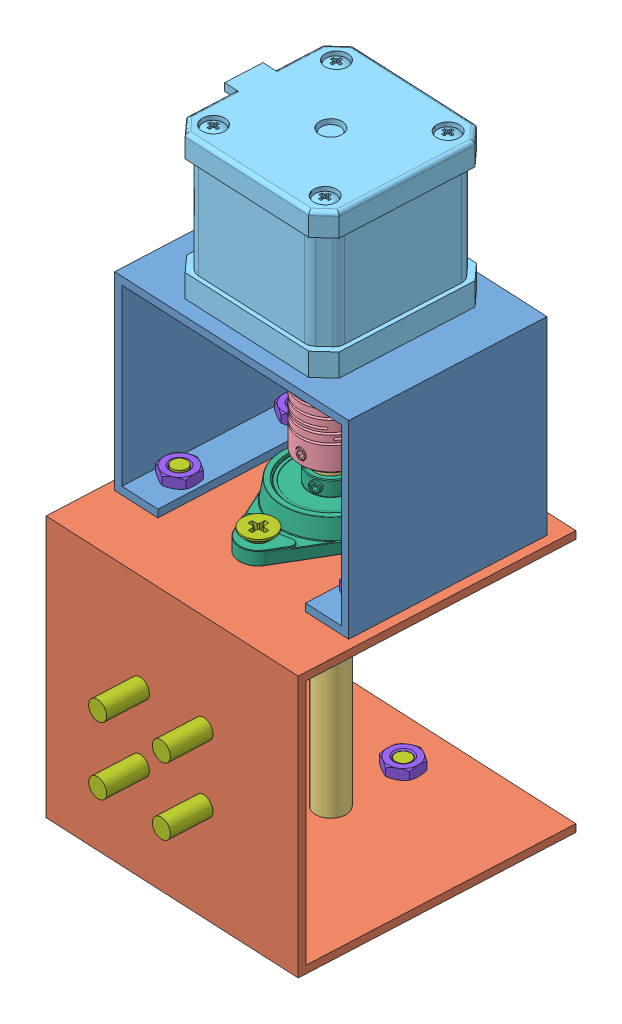
SolidWorks assembly Junta4-Assembly, configuration Valor predeterminado. Lengths in mm.
Overall size (73.29 177 83).
31 component instances, 8 part files, 60 mates.
Components (placement in the parent):
- Junta 4 parte 1-1: Junta 4 parte 1 [Valor predeterminado] at (-23.3214 57.6883 49.324) x (0.998842 0 0.04812) z (-0.04812 0 0.998842) size (65 50 50)
- Junta 4 parte 2-2: Junta 4 parte 2 [Valor predeterminado] at (-52.5649 -26.8117 32.8978) x (0 1 0) z (0.998842 0 0.04812) size (69 70 70)
- Eixo 4-1: Eixo 4 [Valor predeterminado] at (-23.3214 -81.3117 49.324) size (8 110 8)
- Acoplamento Flexível MSTS-16-5-8-1: Acoplamento Flexível MSTS-16-5-8 [Valor predeterminado] at (-23.3214 45.1883 49.324) x (0 -1 0) z (0 0 1) size (23 16 16)
- NEMA17-1: NEMA17 [Défaut] at (-23.3214 55.6883 49.324) x (0.998842 0 0.04812) z (0 1 0) size (45.3 42.3 62)
- Rolamento KFL08 Ø8-1: Rolamento KFL08 Ø8 [Valor predeterminado] at (-23.3214 7.6883 49.324) x (0.04812 0 -0.998842) z (0.998842 0 0.04812) size (47.88 11.35 28.12)
- Rolamento KFL08 Ø8-2: Rolamento KFL08 Ø8 [Valor predeterminado] at (-23.3214 -61.3117 49.324) x (0.04812 0 -0.998842) z (-0.998842 0 -0.04812) size (47.88 11.35 28.12)
- countersunk flat head cross recess screw_iso-1: countersunk flat head cross recess screw_iso [ISO 7046-1 - M5 x 16 - Z - 16N] at (-16.1656 -17.9729 84.4706) x (-0.04812 0 0.998842) z (-0.015193 -0.999884 -0.000732) size (16 9.3 9.3)
- countersunk flat head cross recess screw_iso-2: countersunk flat head cross recess screw_iso [ISO 7046-1 - M5 x 16 - Z - 16N] at (-16.1656 -35.6506 84.4706) x (-0.04812 0 0.998842) z (-0.015193 -0.999884 -0.000732) size (16 9.3 9.3)
- countersunk flat head cross recess screw_iso-3: countersunk flat head cross recess screw_iso [ISO 7046-1 - M5 x 16 - Z - 16N] at (-33.8227 -17.9729 83.6199) x (-0.04812 0 0.998842) z (-0.015193 -0.999884 -0.000732) size (16 9.3 9.3)
- countersunk flat head cross recess screw_iso-4: countersunk flat head cross recess screw_iso [ISO 7046-1 - M5 x 16 - Z - 16N] at (-33.8227 -35.6506 83.6199) x (-0.04812 0 0.998842) z (-0.015193 -0.999884 -0.000732) size (16 9.3 9.3)
- countersunk flat head cross recess screw_iso-9: countersunk flat head cross recess screw_iso [ISO 7046-1 - M4 x 10 - Z - 10N] at (-22.4432 13.2383 31.0952) x (0 -1 0) z (0.999954 0 -0.009545) size (10 8.4 8.4)
- countersunk flat head cross recess screw_iso-12: countersunk flat head cross recess screw_iso [ISO 7046-1 - M4 x 10 - Z - 10N] at (-24.1996 13.2383 67.5529) x (0 -1 0) z (0.999954 0 -0.009545) size (10 8.4 8.4)
- countersunk flat head cross recess screw_iso-13: countersunk flat head cross recess screw_iso [ISO 7046-1 - M4 x 10 - Z - 10N] at (-22.4432 -66.8617 31.0952) x (0 1 0) z (-0.83191 0 -0.55491) size (10 8.4 8.4)
- countersunk flat head cross recess screw_iso-14: countersunk flat head cross recess screw_iso [ISO 7046-1 - M4 x 10 - Z - 10N] at (-24.1996 -66.8617 67.5529) x (0 1 0) z (-0.83191 0 -0.55491) size (10 8.4 8.4)
- countersunk flat head cross recess screw_iso-15: countersunk flat head cross recess screw_iso [ISO 7046-1 - M3 x 6 - Z - 6N] at (-8.5852 53.7069 65.5519) x (0 1 0) z (0.179864 0 -0.983691) size (6 5.5 5.5)
- countersunk flat head cross recess screw_iso-16: countersunk flat head cross recess screw_iso [ISO 7046-1 - M3 x 6 - Z - 6N] at (-39.5493 53.7069 64.0602) x (0 1 0) z (0.179864 0 -0.983691) size (6 5.5 5.5)
- countersunk flat head cross recess screw_iso-17: countersunk flat head cross recess screw_iso [ISO 7046-1 - M3 x 6 - Z - 6N] at (-7.0935 53.7069 34.5878) x (0 1 0) z (0.179864 0 -0.983691) size (6 5.5 5.5)
- countersunk flat head cross recess screw_iso-18: countersunk flat head cross recess screw_iso [ISO 7046-1 - M3 x 6 - Z - 6N] at (-38.0576 53.7069 33.0961) x (0 1 0) z (0.179864 0 -0.983691) size (6 5.5 5.5)
- countersunk flat head cross recess screw_iso-19: countersunk flat head cross recess screw_iso [ISO 7046-1 - M4 x 10 - Z - 10N] at (1.4272 2.5741 65.5337) x (0 1 0) z (-0.00838 0 -0.999965) size (10 8.4 8.4)
- countersunk flat head cross recess screw_iso-20: countersunk flat head cross recess screw_iso [ISO 7046-1 - M4 x 10 - Z - 10N] at (-49.5137 2.5741 63.0796) x (0 1 0) z (-0.00838 0 -0.999965) size (10 8.4 8.4)
- countersunk flat head cross recess screw_iso-21: countersunk flat head cross recess screw_iso [ISO 7046-1 - M4 x 10 - Z - 10N] at (2.8708 2.5741 35.5684) x (0 1 0) z (-0.00838 0 -0.999965) size (10 8.4 8.4)
- countersunk flat head cross recess screw_iso-22: countersunk flat head cross recess screw_iso [ISO 7046-1 - M4 x 10 - Z - 10N] at (-48.0701 2.5741 33.1143) x (0 1 0) z (-0.00838 0 -0.999965) size (10 8.4 8.4)
- hex nut jam_am-1: hex nut jam_am [B18.2.4.5M - Hex jam nut,  M5 x 0.8 --D-N] at (2.8708 12.3883 35.5684) x (1 0 0) z (0 1 0) size (8 9.24 2.7)
- hex nut jam_am-2: hex nut jam_am [B18.2.4.5M - Hex jam nut,  M5 x 0.8 --D-N] at (1.4272 12.3883 65.5337) x (1 0 0) z (0 1 0) size (8 9.24 2.7)
- hex nut jam_am-3: hex nut jam_am [B18.2.4.5M - Hex jam nut,  M5 x 0.8 --D-N] at (-49.5137 12.3883 63.0796) x (1 0 0) z (0 1 0) size (8 9.24 2.7)
- hex nut jam_am-4: hex nut jam_am [B18.2.4.5M - Hex jam nut,  M5 x 0.8 --D-N] at (-48.0701 12.3883 33.1143) x (1 0 0) z (0 1 0) size (8 9.24 2.7)
- hex nut jam_am-5: hex nut jam_am [B18.2.4.5M - Hex jam nut,  M5 x 0.8 --D-N] at (-22.4432 5.6883 31.0952) x (1 0 0) z (0 1 0) size (8 9.24 2.7)
- hex nut jam_am-6: hex nut jam_am [B18.2.4.5M - Hex jam nut,  M5 x 0.8 --D-N] at (-24.1996 5.6883 67.5529) x (1 0 0) z (0 1 0) size (8 9.24 2.7)
- hex nut jam_am-7: hex nut jam_am [B18.2.4.5M - Hex jam nut,  M5 x 0.8 --D-N] at (-22.4432 -56.6117 31.0952) x (1 0 0) z (0 1 0) size (8 9.24 2.7)
- hex nut jam_am-8: hex nut jam_am [B18.2.4.5M - Hex jam nut,  M5 x 0.8 --D-N] at (-24.1996 -56.6117 67.5529) x (1 0 0) z (0 1 0) size (8 9.24 2.7)
Mates (geometry in assembly coordinates):
- Coincident1: coincident: plane of ? through (14.1976 -24.6891 40) normal (0 -1 0); plane of ? through (13.6976 -24.6891 80) normal (0 1 0)
- Concentric2: concentric: cylinder of ? through (9.1976 -32.6891 80) axis (0 1 0) radius 2; cylinder of ? through (9.1976 -37.1891 80) axis (0 1 0) radius 2
- Concentric3: concentric: cylinder of ? through (-41.8024 -32.6891 50) axis (0 1 0) radius 2; cylinder of ? through (-41.8024 -37.1891 50) axis (0 1 0) radius 2
- Coincident3: coincident: plane of ? through (13.6976 -24.6891 80) normal (0 1 0); plane of Rolamento KFL08 Ø8-1 through (-29.8632 -24.6891 65) normal (0 -1 0)
- Concentric7: concentric: circle of Rolamento KFL08 Ø8-1; cylinder of ? through (-16.3024 -91.1891 65) axis (0 1 0) radius 4
- Concentric8: concentric: cylinder of ? through (-16.3024 -93.6891 83.25) axis (0 1 0) radius 2; cylinder of Rolamento KFL08 Ø8-1 through (-16.3024 -22.8891 83.25) axis (0 -1 0) radius 2.5
- Concentric9: concentric: cylinder of ? through (-16.3024 -91.1891 65) axis (0 1 0) radius 4; cylinder of Rolamento KFL08 Ø8-2 through (-16.3024 -99.6141 65) axis (0 1 0) radius 4
- Coincident4: coincident: plane of ? through (13.6976 -93.6891 80) normal (0 -1 0); plane of Rolamento KFL08 Ø8-2 through (-2.7416 -93.6891 65) normal (0 1 0)
- Concentric10: concentric: cylinder of ? through (-16.3024 -93.6891 46.75) axis (0 1 0) radius 2; cylinder of Rolamento KFL08 Ø8-2 through (-16.3024 -95.4891 46.75) axis (0 1 0) radius 2.5
- Coincident5: coincident: circle of Junta 4 parte 1-1; circle of Junta 4 parte 2-2
- Concentric11: concentric: circle of Junta 4 parte 1-1; circle of Junta 4 parte 2-2
- Concentric12: concentric: cylinder of Rolamento KFL08 Ø8-1 through (-23.3214 13.6133 49.324) axis (0 -1 0) radius 4; cylinder of Junta 4 parte 2-2 through (-23.3214 -58.8117 49.324) axis (0 1 0) radius 4
- Concentric13: concentric: circle of Rolamento KFL08 Ø8-1; circle of Junta 4 parte 2-2
- Coincident7: coincident: plane of Rolamento KFL08 Ø8-1 through (-36.8665 7.6883 48.6715) normal (0 -1 0); plane of Junta 4 parte 2-2 through (-52.5649 7.6883 32.8978) normal (0 1 0)
- Concentric14: concentric: cylinder of Rolamento KFL08 Ø8-2 through (-24.1996 -63.1117 67.5529) axis (0 1 0) radius 2.5; cylinder of Junta 4 parte 2-2 through (-24.1996 -61.3117 67.5529) axis (0 1 0) radius 2
- Concentric15: concentric: cylinder of Rolamento KFL08 Ø8-2 through (-23.3214 -67.2367 49.324) axis (0 1 0) radius 4; cylinder of Junta 4 parte 2-2 through (-23.3214 -58.8117 49.324) axis (0 1 0) radius 4
- Coincident8: coincident: line of Rolamento KFL08 Ø8-2 through (-26.7778 -61.3117 31.8515) axis (-0.507796 0 0.861477); plane of Junta 4 parte 2-2 through (-52.5649 -61.3117 32.8978) normal (0 -1 0)
- Concentric16: concentric: cylinder of Eixo 4-1 through (-23.3214 28.6883 49.324) axis (0 -1 0) radius 4; cylinder of Junta 4 parte 2-2 through (-23.3214 -58.8117 49.324) axis (0 1 0) radius 4
- Coincident9: coincident: plane of Junta 4 parte 1-1 through (-23.3214 57.6883 49.324) normal (0 1 0); plane of NEMA17-1 through (-23.3214 57.6883 49.324) normal (0 -1 0)
- Concentric17: concentric: cylinder of Junta 4 parte 1-1 through (-39.5493 7.6883 64.0602) axis (0 1 0) radius 1.5; cylinder of NEMA17-1 through (-39.5493 119.6883 64.0602) axis (0 -1 0) radius 1.5
- Concentric18: concentric: cylinder of Junta 4 parte 1-1 through (-7.0935 7.6883 34.5878) axis (0 1 0) radius 1.5; cylinder of NEMA17-1 through (-7.0935 119.6883 34.5878) axis (0 -1 0) radius 1.5
- Distance1: distance = 5 mm: plane of Eixo 4-1 through (-23.3214 28.6883 49.324) normal (0 1 0); plane of NEMA17-1 through (-23.3214 33.6883 49.324) normal (0 -1 0)
- Coincident11: coincident: circle of Junta 4 parte 2-2; circle of countersunk flat head cross recess screw_iso-1
- Coincident12: coincident: circle of Junta 4 parte 2-2; circle of countersunk flat head cross recess screw_iso-4
- Coincident13: coincident: circle of Junta 4 parte 2-2; circle of countersunk flat head cross recess screw_iso-2
- Coincident14: coincident: circle of Junta 4 parte 2-2; circle of countersunk flat head cross recess screw_iso-3
- Concentric19: concentric: cylinder of Rolamento KFL08 Ø8-1 through (-22.4432 9.4883 31.0952) axis (0 -1 0) radius 2.5; circle of countersunk flat head cross recess screw_iso-9
- Distance2: distance = 2.05 mm: plane of countersunk flat head cross recess screw_iso-9 through (-22.4432 13.2383 31.0952) normal (0 1 0); plane of Rolamento KFL08 Ø8-1 through (-22.5176 11.1883 32.6387) normal (0 1 0)
- Concentric20: concentric: cylinder of Rolamento KFL08 Ø8-1 through (-24.1996 9.4883 67.5529) axis (0 -1 0) radius 2.5; circle of countersunk flat head cross recess screw_iso-12
- Coincident17: coincident: plane of countersunk flat head cross recess screw_iso-9 through (-22.4432 13.2383 31.0952) normal (0 1 0); plane of countersunk flat head cross recess screw_iso-12 through (-24.1996 13.2383 67.5529) normal (0 1 0)
- Concentric21: concentric: circle of Junta 4 parte 2-2; cylinder of countersunk flat head cross recess screw_iso-14 through (-24.1996 -73.2117 67.5529) axis (0 -1 0) radius 2
- Distance3: distance = 2.05 mm: plane of countersunk flat head cross recess screw_iso-14 through (-24.1996 -66.8617 67.5529) normal (0 -1 0); plane of Rolamento KFL08 Ø8-2 through (-24.1253 -64.8117 66.0093) normal (0 -1 0)
- Concentric22: concentric: cylinder of Rolamento KFL08 Ø8-2 through (-22.4432 -63.1117 31.0952) axis (0 1 0) radius 2.5; cylinder of countersunk flat head cross recess screw_iso-13 through (-22.4432 -73.2117 31.0952) axis (0 -1 0) radius 2
- Coincident20: coincident: plane of countersunk flat head cross recess screw_iso-13 through (-22.4432 -66.8617 31.0952) normal (0 -1 0); plane of countersunk flat head cross recess screw_iso-14 through (-24.1996 -66.8617 67.5529) normal (0 -1 0)
- Coincident22: coincident: circle of Junta 4 parte 1-1; circle of countersunk flat head cross recess screw_iso-18
- Coincident23: coincident: circle of Junta 4 parte 1-1; circle of countersunk flat head cross recess screw_iso-17
- Coincident25: coincident: circle of Junta 4 parte 1-1; circle of countersunk flat head cross recess screw_iso-15
- Coincident26: coincident: circle of Junta 4 parte 1-1; circle of countersunk flat head cross recess screw_iso-16
- Coincident27: coincident: circle of Junta 4 parte 2-2; circle of countersunk flat head cross recess screw_iso-21
- Coincident28: coincident: circle of Junta 4 parte 2-2; circle of countersunk flat head cross recess screw_iso-19
- Coincident29: coincident: circle of Junta 4 parte 2-2; circle of countersunk flat head cross recess screw_iso-20
- Coincident30: coincident: circle of Junta 4 parte 2-2; circle of countersunk flat head cross recess screw_iso-22
- Concentric25: concentric: cylinder of Eixo 4-1 through (-23.3214 28.6883 49.324) axis (0 -1 0) radius 4; cylinder of Acoplamento Flexível MSTS-16-5-8-1 through (-23.3214 22.1883 49.324) axis (0 1 0) radius 8
- Coincident32: coincident: circle of Eixo 4-1; circle of Acoplamento Flexível MSTS-16-5-8-1
- Coincident33: coincident: plane of Junta 4 parte 1-1 through (-4.0482 9.6883 75.2815) normal (0 1 0); plane of hex nut jam_am-1 through (2.8708 9.6883 30.9496) normal (0 -1 0)
- Concentric26: concentric: cylinder of countersunk flat head cross recess screw_iso-21 through (2.8708 -3.7759 35.5684) axis (0 -1 0) radius 2; cylinder of hex nut jam_am-1 through (2.8708 9.6883 35.5684) axis (0 1 0) radius 2.1
- Coincident34: coincident: plane of Junta 4 parte 1-1 through (-4.0482 9.6883 75.2815) normal (0 1 0); plane of hex nut jam_am-2 through (1.4272 9.6883 60.9149) normal (0 -1 0)
- Concentric27: concentric: cylinder of countersunk flat head cross recess screw_iso-19 through (1.4272 -3.7759 65.5337) axis (0 -1 0) radius 2; circle of hex nut jam_am-2
- Coincident35: coincident: plane of Junta 4 parte 1-1 through (-45.0007 9.6883 73.3086) normal (0 1 0); plane of hex nut jam_am-3 through (-49.5137 9.6883 58.4608) normal (0 -1 0)
- Concentric28: concentric: cylinder of countersunk flat head cross recess screw_iso-20 through (-49.5137 -3.7759 63.0796) axis (0 -1 0) radius 2; cylinder of hex nut jam_am-3 through (-49.5137 9.6883 63.0796) axis (0 1 0) radius 2.1
- Concentric29: concentric: cylinder of countersunk flat head cross recess screw_iso-22 through (-48.0701 -3.7759 33.1143) axis (0 -1 0) radius 2; cylinder of hex nut jam_am-4 through (-48.0701 9.6883 33.1143) axis (0 1 0) radius 2.1
- Coincident36: coincident: plane of Junta 4 parte 1-1 through (-45.0007 9.6883 73.3086) normal (0 1 0); plane of hex nut jam_am-4 through (-48.0701 9.6883 28.4955) normal (0 -1 0)
- Concentric30: concentric: cylinder of countersunk flat head cross recess screw_iso-12 through (-24.1996 19.5883 67.5529) axis (0 1 0) radius 2; cylinder of hex nut jam_am-6 through (-24.1996 2.9883 67.5529) axis (0 1 0) radius 2.1
- Concentric31: concentric: cylinder of countersunk flat head cross recess screw_iso-9 through (-22.4432 19.5883 31.0952) axis (0 1 0) radius 2; cylinder of hex nut jam_am-5 through (-22.4432 2.9883 31.0952) axis (0 1 0) radius 2.1
- Coincident37: coincident: plane of Junta 4 parte 2-2 through (-52.5649 5.6883 32.8978) normal (0 -1 0); plane of hex nut jam_am-5 through (-22.4432 5.6883 26.4764) normal (0 1 0)
- Coincident38: coincident: plane of Junta 4 parte 2-2 through (-52.5649 5.6883 32.8978) normal (0 -1 0); plane of hex nut jam_am-6 through (-24.1996 5.6883 62.9341) normal (0 1 0)
- Concentric32: concentric: cylinder of countersunk flat head cross recess screw_iso-13 through (-22.4432 -73.2117 31.0952) axis (0 -1 0) radius 2; cylinder of hex nut jam_am-7 through (-22.4432 -59.3117 31.0952) axis (0 1 0) radius 2.1
- Concentric33: concentric: cylinder of countersunk flat head cross recess screw_iso-14 through (-24.1996 -73.2117 67.5529) axis (0 -1 0) radius 2; cylinder of hex nut jam_am-8 through (-24.1996 -59.3117 67.5529) axis (0 1 0) radius 2.1
- Coincident39: coincident: plane of Junta 4 parte 2-2 through (-52.5649 -59.3117 32.8978) normal (0 1 0); plane of hex nut jam_am-7 through (-22.4432 -59.3117 26.4764) normal (0 -1 0)
- Coincident40: coincident: plane of Junta 4 parte 2-2 through (-52.5649 -59.3117 32.8978) normal (0 1 0); plane of hex nut jam_am-8 through (-24.1996 -59.3117 62.9341) normal (0 -1 0)
